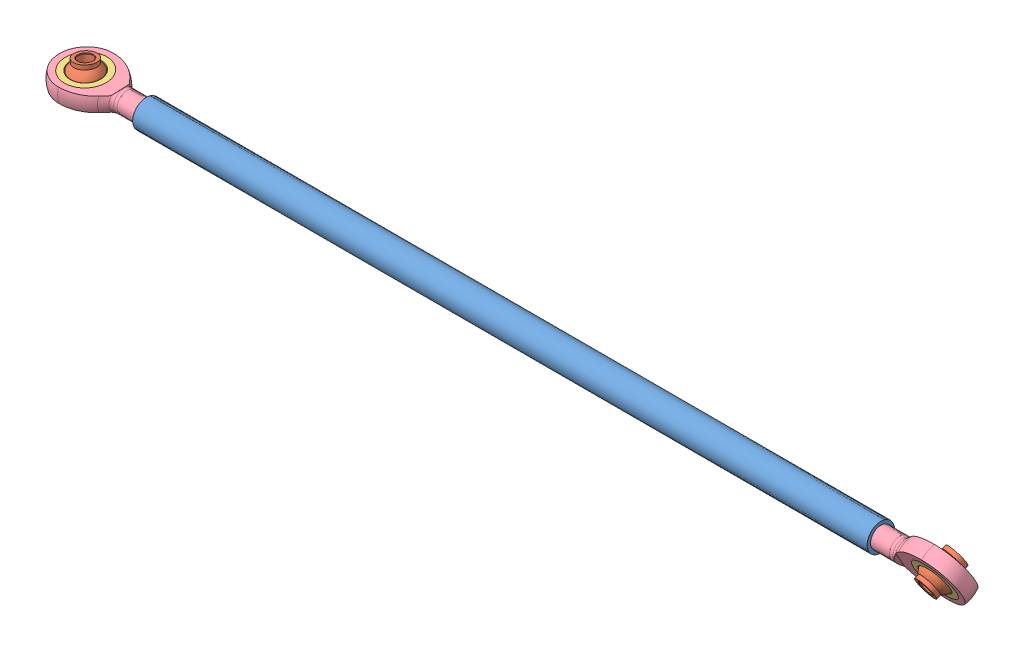
SolidWorks assembly Rear Pull Rod, configuration Default. Lengths in mm.
Overall size (430.83 63.12 62.57).
9 component instances, 4 part files, 4 mates.
Components (placement in the parent):
- Rear Pull Rod-1: Rear Pull Rod [Default<As Machined>] at (-85.4005 206.4804 295.8455) size (338.1 12.7 12.7)
- HXAM-4T Rod End-1: HXAM-4T Rod End [Default] at (-113.2008 206.4804 295.8455) x (0.965627 0.087659 -0.244705) z (0.236655 0.092903 0.967142) size (69.2 35.42 44.66) (flexible)
  - HXAM-4T Ball-1: HXAM-4T Ball [Default] at (0 0 -49.2252) size (15.06 15.06 15.06)
  - HXAM-4T Sleeve-1: HXAM-4T Sleeve [Default] at (47.5332 -5.2923 11.6494) x (-0.247981 -0.108146 0.96271) z (-0.965627 0.107513 -0.236655) size (19.53 6.73 19.53)
  - HXAM-4T Housing-1: HXAM-4T Housing [Default] at (47.5332 -5.2923 11.6494) x (-0.247981 -0.108146 0.96271) z (-0.965627 0.107513 -0.236655) size (27.48 26.04 62.51)
- HXAM-4T Rod End-2: HXAM-4T Rod End [Default] at (280.4992 206.4804 295.8455) x (-0.980034 0.198827 -0.000973) z (-0.169188 -0.836493 -0.521206) size (68.56 33.24 38.87) (flexible)
  - HXAM-4T Ball-1: HXAM-4T Ball [Default] at (0 0 -49.2252) size (15.06 15.06 15.06)
  - HXAM-4T Sleeve-1: HXAM-4T Sleeve [Default] at (48.2424 -5.1412 8.3283) x (-0.173187 -0.030424 0.984419) z (-0.980034 0.104443 -0.169188) size (19.53 6.73 19.53)
  - HXAM-4T Housing-1: HXAM-4T Housing [Default] at (48.2424 -5.1412 8.3283) x (-0.173187 -0.030424 0.984419) z (-0.980034 0.104443 -0.169188) size (27.48 26.04 62.51)
Mates (geometry in assembly coordinates):
- Concentric1: concentric anti-aligned: cylinder of HXAM-4T Rod End-1/HXAM-4T Housing-1 through (-79.3667 206.4804 295.8455) axis (1 0 0) radius 4.7625; cylinder of Rear Pull Rod-1 through (252.6989 206.4804 295.8455) axis (-1 0 0) radius 6.35
- Concentric2: concentric aligned: cylinder of ? through (246.6651 206.4804 295.8455) axis (-1 0 0) radius 4.7625; cylinder of Rear Pull Rod-1 through (252.6989 206.4804 295.8455) axis (-1 0 0) radius 6.35
- Coincident1: coincident: point of HXAM-4T Rod End-2/HXAM-4T Ball-1; point of Rear Pull Rod-1
- Coincident2: coincident: point of HXAM-4T Rod End-1/HXAM-4T Ball-1; point of Rear Pull Rod-1
